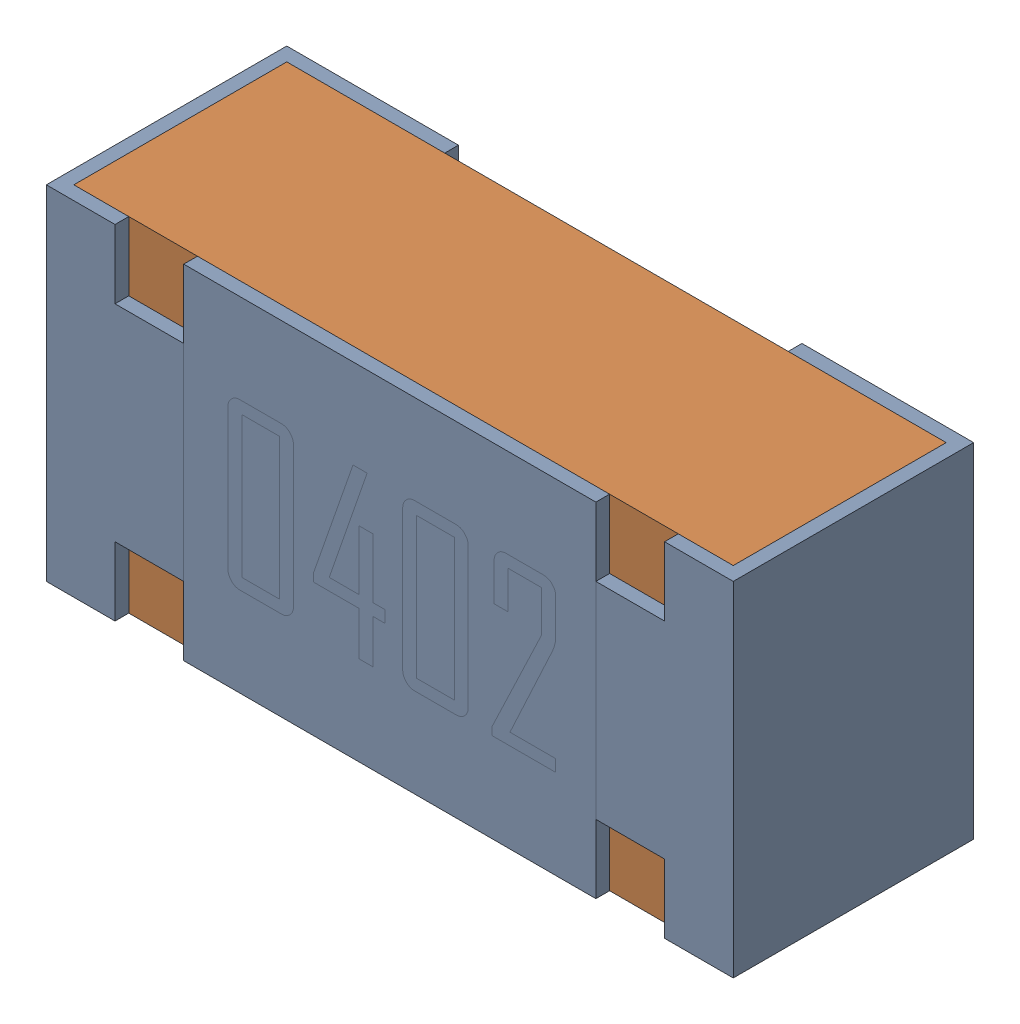
SolidWorks assembly R5, configuration Default. Lengths in mm.
Overall size (1 0.5 0.35).
3 component instances, 2 part files, 0 mates.
Components (placement in the parent):
- R5-subassembly-1-1: R5-subassembly-1 [Default] at (-6.5001 -11 0) x (1 0 0) z (0 -1 0) size (1 0.35 0.5)
  - 0402 resistor-1: 0402 resistor [Default] at origin size (1 0.35 0.5)
  - 0402 resistor-1-1: 0402 resistor-1 [Default] at origin size (0.96 0.31 0.5)
